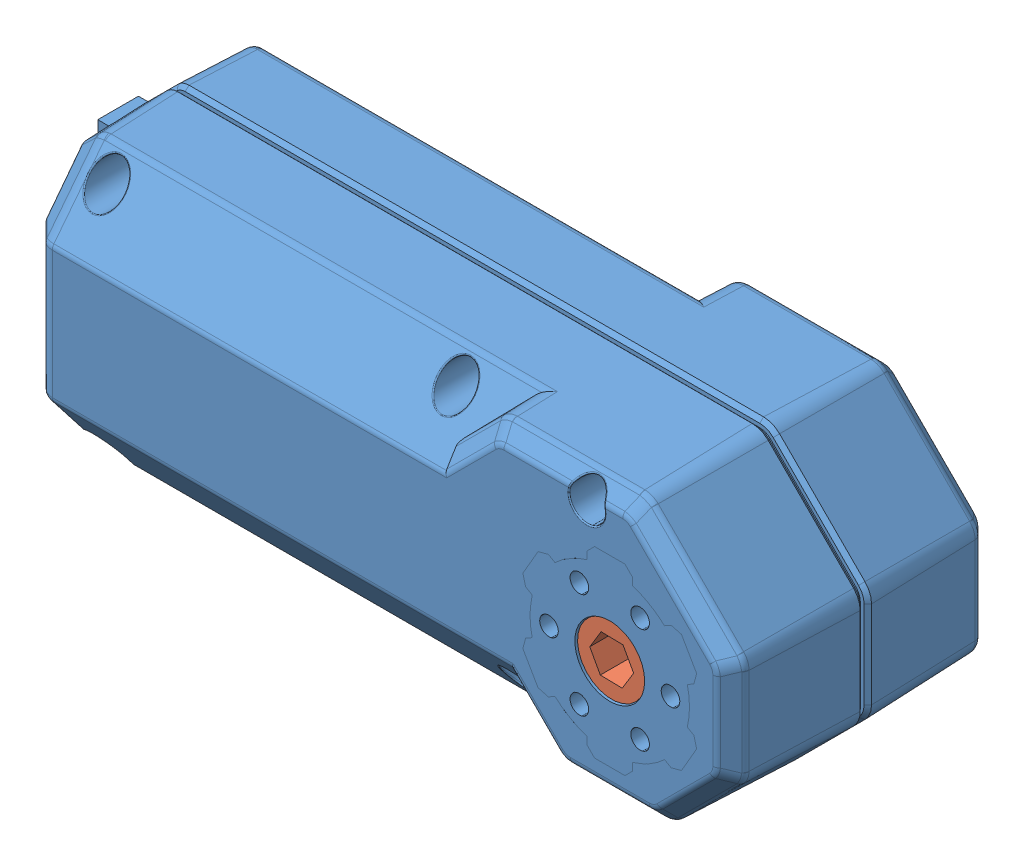
SolidWorks assembly MotorCoreHexRotating, configuration Default. Lengths in mm.
Overall size (103.31 42.79 34.54).
2 component instances, 2 part files, 2 mates.
Components (placement in the parent):
- PART_MotorCoreHex_Shell-1: PART_MotorCoreHex_Shell [Default] at (61.6102 67.8569 71.4745) size (100 42.79 34.54)
- PART_MotorCoreHex_Core-1: PART_MotorCoreHex_Core [Default] at (61.6102 67.8569 71.1205) x (-0.633356 0.77386 0) z (0 0 1) size (28.16 28.13 34)
Mates (geometry in assembly coordinates):
- Concentric1: concentric aligned: cylinder of PART_MotorCoreHex_Shell-1 through (61.6102 67.8569 84.8745) axis (0 0 1) radius 4.6; cylinder of PART_MotorCoreHex_Core-1 through (61.6102 67.8569 69.4705) axis (0 0 1) radius 4.5
- Distance2: distance = 0.254 mm aligned: plane of PART_MotorCoreHex_Core-1 through (61.6102 67.8569 87.4705) normal (0 0 1); plane of PART_MotorCoreHex_Shell-1 through (61.6102 67.8569 87.7245) normal (0 0 1)
